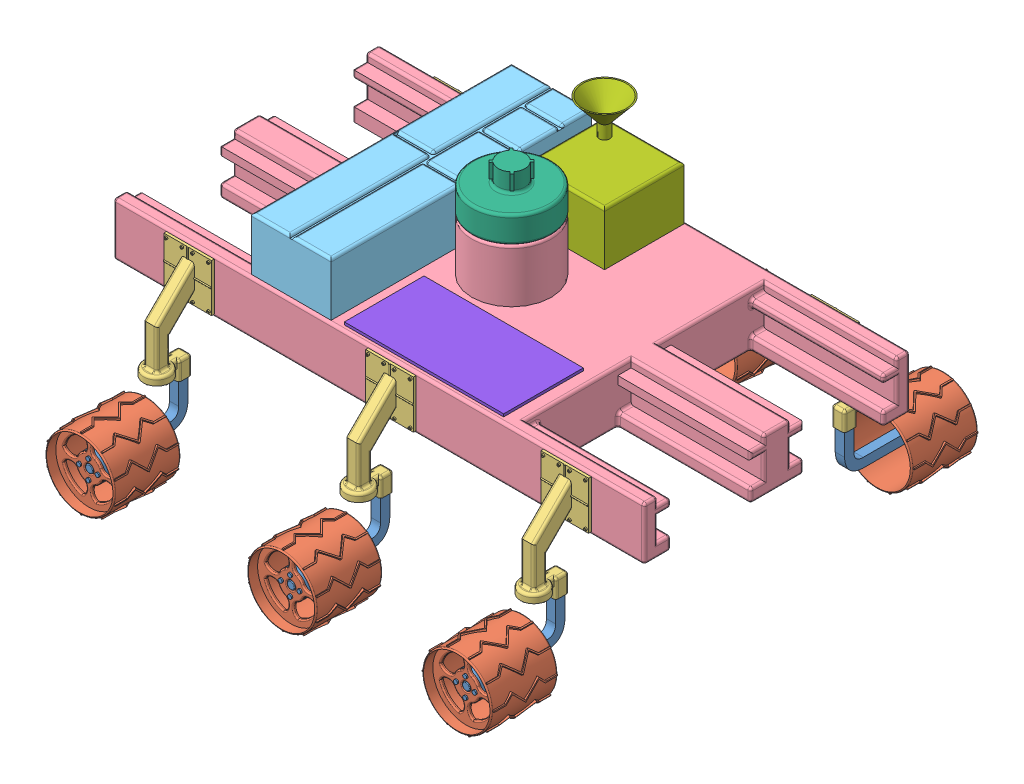
SolidWorks assembly lg, configuration Default. Lengths in mm.
Overall size (2000 1056.21 1833.55).
23 component instances, 8 part files, 38 mates.
Components (placement in the parent):
- act2-1: act2 [Default] at (710 -374.097 990.1927) x (0 1 0) z (1 0 0) size (227.86 360.36 100)
- Wheel-1: Wheel [Default] at (710 -349.0008 1023.6376) x (0 1 0) z (0 0 -1) size (274.42 270 250)
- act1-1: act1 [Default] at (710 -171.1455 626.4214) x (-1 0 0) z (0 0 -1) size (180 401.15 176.42)
- body-1: body [Default] at origin size (2000 400 1000)
- act1-2: act1 [Default] at (-710 -171.1455 626.4214) x (-1 0 0) z (0 0 -1) size (180 401.15 176.42)
- Wheel-2: Wheel [Default] at (-710 -349.0008 1023.6376) x (-1 0 0) z (0 0 -1) size (274.42 270 250)
- act2-2: act2 [Default] at (-710 -374.097 990.1927) x (0 1 0) z (1 0 0) size (227.86 360.36 100)
- Wheel-3: Wheel [Default] at (-710 -349.0008 -1023.6376) size (274.42 270 250)
- act2-3: act2 [Default] at (-710 -374.097 -990.1927) x (0 1 0) z (-1 0 0) size (227.86 360.36 100)
- act1-3: act1 [Default] at (-710 -171.1455 -626.4214) size (180 401.15 176.42)
- act1-4: act1 [Default] at (710 -171.1455 -626.4214) size (180 401.15 176.42)
- Wheel-4: Wheel [Default] at (710 -349.0008 -1023.6376) x (0 -1 0) z (0 0 1) size (274.42 270 250)
- act2-4: act2 [Default] at (710 -374.097 -990.1927) x (0 1 0) z (-1 0 0) size (227.86 360.36 100)
- tool box-1: tool box [Default] at (-340 200 0) x (0 0 1) z (-1 0 0) size (980 200 300)
- act1-5: act1 [Default] at (50 -171.1455 626.4214) x (-1 0 0) z (0 0 -1) size (180 401.15 176.42)
- act2-5: act2 [Default] at (50 -374.097 990.1927) x (0 1 0) z (1 0 0) size (227.86 360.36 100)
- Wheel-5: Wheel [Default] at (50 -349.0008 1023.6376) x (-1 0 0) z (0 0 -1) size (274.42 270 250)
- arm-1: arm [Default] at (0 400 0) x (0.719935 0 0.694042) z (-0.694042 0 0.719935) size (300 300 300)
- Lab-1: Lab [Default] at (10 200 -340) x (0 0 1) z (-1 0 0) size (324.09 330 324.09)
- Wheel-6: Wheel [Default] at (50 -349.0008 -1023.6376) size (274.42 270 250)
- act1-6: act1 [Default] at (50 -171.1455 -626.4214) size (180 401.15 176.42)
- act2-6: act2 [Default] at (50 -374.097 -990.1927) x (0 1 0) z (-1 0 0) size (227.86 360.36 100)
- solar panel-1: solar panel [Default] at (150 200 330) size (600 10 300)
Mates (geometry in assembly coordinates):
- Coincident1: coincident: plane of act2-1 through (710 -349.0008 871.7767) normal (0 0 1); plane of Wheel-1 through (710 -349.0008 871.7767) normal (0 0 -1)
- Concentric1: concentric: cylinder of act2-1 through (745 -349.0008 881.7767) axis (0 0 -1) radius 5; cylinder of Wheel-1 through (745 -349.0008 871.7767) axis (0 0 1) radius 5
- Concentric2: concentric: cylinder of act2-1 through (675 -349.0008 881.7767) axis (0 0 -1) radius 5; cylinder of Wheel-1 through (675 -349.0008 871.7767) axis (0 0 1) radius 5
- Coincident2: coincident: plane of act1-1 through (710 -171.1455 500) normal (0 0 -1); plane of body-1 through (500 200 500) normal (0 0 1)
- Coincident5: coincident: plane of body-1 through (500 200 500) normal (0 0 1); plane of act1-2 through (-710 -171.1455 500) normal (0 0 -1)
- Coincident13: coincident: plane of act2-1 through (692.5 -171.1455 526.4214) normal (0 1 0); plane of act1-1 through (710 -171.1455 626.4214) normal (0 -1 0)
- Coincident14: coincident: line of act2-1 through (692.5 -171.1455 526.4214) axis (1 0 0); line of act1-1 through (692.5 -171.1455 526.4214) axis (1 0 0)
- Coincident15: coincident: line of act2-1 through (692.5 -171.1455 526.4214) axis (0 0 1); line of act1-1 through (692.5 -171.1455 561.4214) axis (0 0 -1)
- Coincident16: coincident: plane of act1-2 through (-710 -171.1455 626.4214) normal (0 -1 0); plane of act2-2 through (-727.5 -171.1455 526.4214) normal (0 1 0)
- Coincident17: coincident: line of act1-2 through (-727.5 -171.1455 561.4214) axis (1 0 0); line of act2-2 through (-727.5 -171.1455 561.4214) axis (1 0 0)
- Coincident18: coincident: line of act1-2 through (-692.5 -171.1455 561.4214) axis (0 0 -1); line of act2-2 through (-692.5 -171.1455 526.4214) axis (0 0 1)
- Concentric3: concentric: cylinder of Wheel-2 through (-710 -349.0008 871.7767) axis (0 0 1) radius 15; cylinder of act2-2 through (-710 -349.0008 881.7767) axis (0 0 -1) radius 15
- Concentric4: concentric: cylinder of Wheel-2 through (-710 -384.0008 871.7767) axis (0 0 1) radius 5; cylinder of act2-2 through (-710 -384.0008 881.7767) axis (0 0 -1) radius 5
- Coincident20: coincident: plane of Wheel-2 through (-710 -349.0008 871.7767) normal (0 0 -1); plane of act2-2 through (-710 -349.0008 871.7767) normal (0 0 1)
- Coincident22: coincident: line of act1-1 through (620 190 500) axis (1 0 0); plane of body-1 through (500 200 500) normal (0 0 1)
- Coincident24: coincident: line of body-1 through (990 190 500) axis (-1 0 0); line of act1-2 through (-800 190 500) axis (1 0 0)
- Coincident26: coincident: plane of body-1 through (0 200 0) normal (0 1 0); plane of tool box-1 through (-340 200 0) normal (0 -1 0)
- Coincident27: coincident: line of body-1 through (-490 200 40) axis (0 0 1); line of tool box-1 through (-490 200 -490) axis (0 0 1)
- Coincident28: coincident: line of body-1 through (990 200 -490) axis (-1 0 0); line of tool box-1 through (-190 200 -490) axis (-1 0 0)
- Distance1: distance = 200 mm: plane of body-1 through (-1000 0 0) normal (-1 0 0); plane of act1-2 through (-800 10 500) normal (-1 0 0)
- Distance2: distance = 200 mm: plane of act1-1 through (800 10 500) normal (1 0 0); plane of body-1 through (1000 0 0) normal (1 0 0)
- Coincident31: coincident: plane of body-1 through (500 200 500) normal (0 0 1); plane of act1-5 through (50 -171.1455 500) normal (0 0 -1)
- Coincident33: coincident: line of body-1 through (990 190 500) axis (-1 0 0); line of act1-5 through (-40 190 500) axis (1 0 0)
- Distance3: distance = 480 mm: plane of act1-5 through (140 10 500) normal (1 0 0); plane of act1-1 through (620 10 500) normal (-1 0 0)
- Coincident35: coincident: plane of act1-5 through (50 -171.1455 626.4214) normal (0 -1 0); plane of act2-5 through (32.5 -171.1455 526.4214) normal (0 1 0)
- Coincident36: coincident: line of act1-5 through (32.5 -171.1455 561.4214) axis (1 0 0); line of act2-5 through (32.5 -171.1455 561.4214) axis (1 0 0)
- Coincident37: coincident: line of act1-5 through (67.5 -171.1455 561.4214) axis (0 0 -1); line of act2-5 through (67.5 -171.1455 526.4214) axis (0 0 1)
- Coincident38: coincident: plane of act2-5 through (50 -349.0008 871.7767) normal (0 0 1); plane of Wheel-5 through (50 -349.0008 871.7767) normal (0 0 -1)
- Concentric5: concentric: cylinder of act2-5 through (50 -349.0008 881.7767) axis (0 0 -1) radius 15; cylinder of Wheel-5 through (50 -349.0008 871.7767) axis (0 0 1) radius 15
- Concentric6: concentric: cylinder of act2-5 through (85 -349.0008 881.7767) axis (0 0 -1) radius 5; cylinder of Wheel-5 through (85 -349.0008 871.7767) axis (0 0 1) radius 5
- Coincident39: coincident: plane of body-1 through (0 400 0) normal (0 1 0); plane of arm-1 through (0 400 0) normal (0 -1 0)
- Coincident40: coincident: cylinder of body-1 through (0 400 0) axis (0 -1 0) radius 150; circle of arm-1
- Coincident41: coincident: plane of body-1 through (0 200 0) normal (0 1 0); plane of Lab-1 through (10 200 -340) normal (0 -1 0)
- Coincident43: coincident: line of body-1 through (990 200 -490) axis (-1 0 0); line of Lab-1 through (160 200 -490) axis (-1 0 0)
- Distance5: distance = 50 mm: plane of Lab-1 through (-140 400 -490) normal (-1 0 0); plane of tool box-1 through (-190 400 490) normal (1 0 0)
- Coincident45: coincident: plane of body-1 through (0 200 0) normal (0 1 0); plane of solar panel-1 through (150 200 330) normal (0 -1 0)
- Distance6: distance = 50 mm: plane of solar panel-1 through (450 210 480) normal (1 0 0); plane of body-1 through (500 200 500) normal (1 0 0)
- Distance7: distance = 20 mm: plane of body-1 through (500 200 500) normal (0 0 1); plane of solar panel-1 through (450 210 480) normal (0 0 1)
